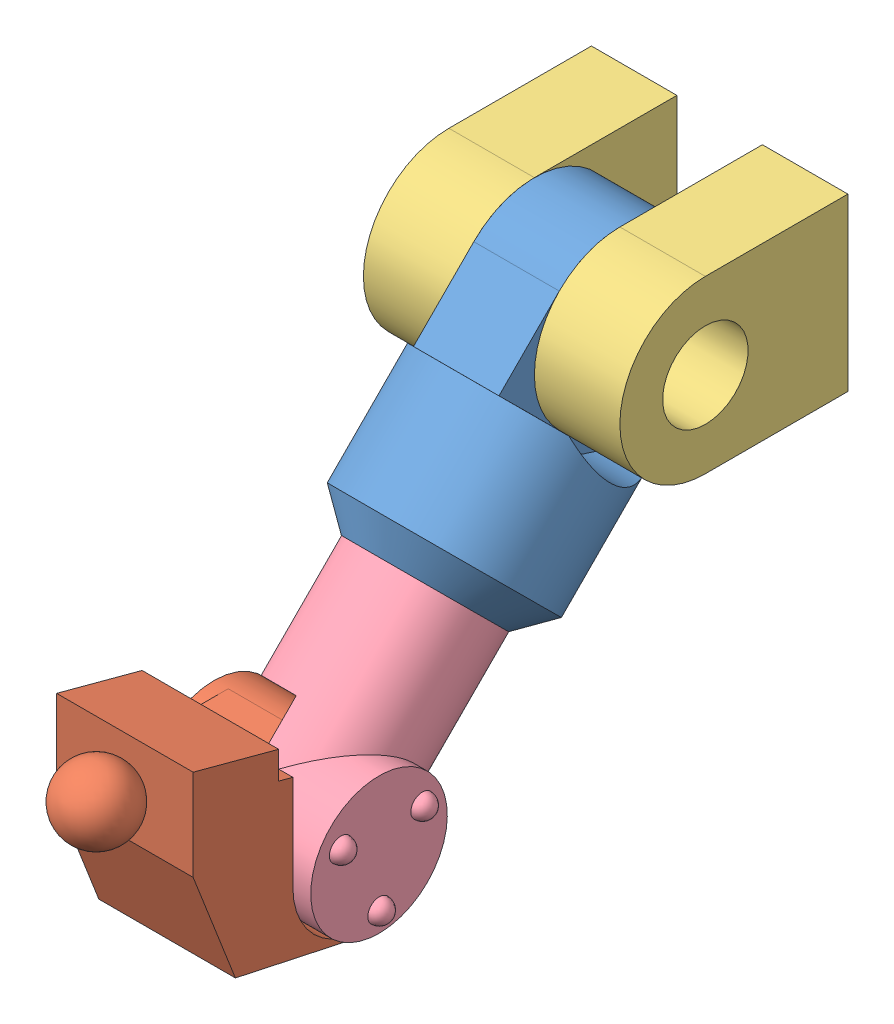
SolidWorks assembly WALL-E NECK ASSEMBLY, configuration Default. Lengths in mm.
Overall size (29.03 58.25 76.95).
5 component instances, 4 part files, 10 mates.
Components (placement in the parent):
- WALL-E NECK-1: WALL-E NECK [Default] at (1216.8967 386.927 32.5054) x (0 -0.708862 0.705347) z (1 0 0) size (35.35 21.64 21.64)
- WALL-E NECK (PIVOT)-1: WALL-E NECK (PIVOT) [Default] at (1215.4387 363.9974 69.005) x (0 -1 0) z (-1 0 0) size (26.07 35.88 18.83)
- WALL-E NECK (SUPPORT)-1: WALL-E NECK (SUPPORT) [Default] at (1206.3272 392.596 23.6376) x (0 1 0) z (1 0 0) size (19.36 25.81 9.68)
- WALL-E NECK (SUPPORT)-2: WALL-E NECK (SUPPORT) [Default] at (1225.682 392.596 23.6376) x (0 1 0) z (1 0 0) size (19.36 25.81 9.68)
- WALL-E NECK (CYLINDER)-1: WALL-E NECK (CYLINDER) [Default] at (1218.3547 364.345 54.9754) x (0 -0.705347 -0.708862) z (-1 0 0) size (15.46 28.36 18.81)
Mates (geometry in assembly coordinates):
- Concentric1: concentric: cylinder of assembly; cylinder of assembly; cylinder of WALL-E NECK-1 through (1211.1659 392.596 26.8646) axis (1 0 0) radius 4.8387; cylinder of WALL-E NECK (SUPPORT)-2 through (1220.8433 392.596 26.8646) axis (1 0 0) radius 4.8387
- Coincident1: coincident: plane of assembly; plane of assembly; plane of WALL-E NECK-1 through (1220.8433 391.4464 28.0085) normal (1 0 0); plane of WALL-E NECK (SUPPORT)-2 through (1220.8433 392.596 21.9442) normal (-1 0 0)
- Coincident2: coincident: plane of assembly; plane of assembly; plane of WALL-E NECK-1 through (1211.1659 391.4464 28.0085) normal (-1 0 0); plane of WALL-E NECK (SUPPORT)-1 through (1211.1659 392.596 21.9442) normal (1 0 0)
- Concentric3: concentric: cylinder of assembly; cylinder of assembly; cylinder of WALL-E NECK-1 through (1211.1659 392.596 26.8646) axis (1 0 0) radius 4.8387; cylinder of WALL-E NECK (SUPPORT)-1 through (1201.4885 392.596 26.8646) axis (1 0 0) radius 4.8387
- Coincident3: coincident: plane of assembly; plane of assembly; plane of WALL-E NECK (PIVOT)-1 through (1216.8967 360.327 63.1386) normal (1 0 0); plane of WALL-E NECK (CYLINDER)-1 through (1216.8967 352.4872 70.2729) normal (-1 0 0)
- Concentric4: concentric: cylinder of assembly; cylinder of assembly; cylinder of WALL-E NECK (PIVOT)-1 through (1216.8967 359.7708 59.527) axis (-1 0 0) radius 7.7292; cylinder of WALL-E NECK (CYLINDER)-1 through (1226.2388 359.7708 59.527) axis (-1 0 0) radius 7.7292
- Concentric5: concentric: cylinder of assembly; cylinder of assembly; cylinder of WALL-E NECK-1 through (1216.8967 383.4494 35.9659) axis (0 -0.708862 0.705347) radius 7.7292; cylinder of WALL-E NECK (CYLINDER)-1 through (1216.8967 359.7708 59.527) axis (0 0.708862 -0.705347) radius 7.7292
- Coincident4: coincident: circle of assembly; plane of assembly; circle of WALL-E NECK-1; plane of WALL-E NECK (CYLINDER)-1 through (1216.8967 374.3982 44.9721) normal (0 0.708862 -0.705347)
- Parallel1: parallel: plane of assembly; plane of assembly; plane of WALL-E NECK (PIVOT)-1 through (1224.6259 376.7609 78.9529) normal (0 0 1); plane of WALL-E NECK (SUPPORT)-2 through (1220.8433 402.2734 10.7331) normal (0 0 -1)
- Parallel2: parallel: plane of assembly; plane of assembly; plane of WALL-E NECK (SUPPORT)-1 through (1201.4885 402.2734 10.7331) normal (0 0 -1); plane of WALL-E NECK (SUPPORT)-2 through (1220.8433 402.2734 10.7331) normal (0 0 -1)
